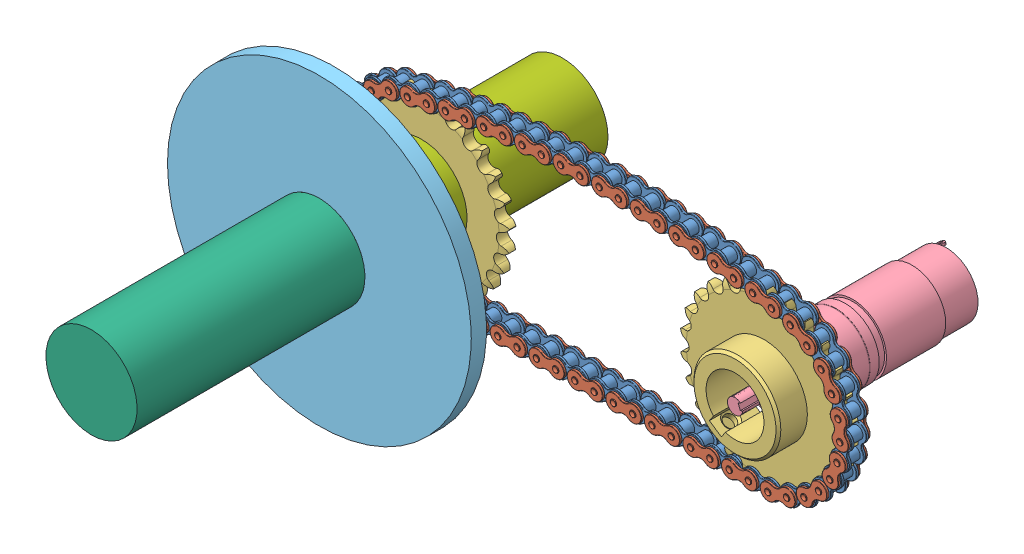
SolidWorks assembly Assem 2, configuration Default. Lengths in mm.
Overall size (403.81 200 344.19).
11 component instances, 7 part files, 6 mates.
Components (placement in the parent):
- chain drive and dc motor-1: chain drive and dc motor [Default] at (729.7386 963.1257 280.6982) x (-1 0 0) z (0 0 1) size (376.19 156.56 146)
  - Chain Drive-1: Chain Drive [Default] at (171.0759 206.2614 266.5858) size (376.19 156.56 30.44)
    - Chain A-1: Chain A [Default] at (-3.9373 5.8722 -1.9118) size (345.06 131.12 15.57)
      - Inner Chain-1: Inner Chain [Default] at (120.3815 217.874 272.3658) size (345.06 131.12 11.1)
      - Outer Chain-1: Outer Chain [Default] at (158.3912 217.874 270.6371) size (343.48 129.27 15.57)
    - Sprocket-1: Sprocket [Default] at (14.8599 170.457 272.397) x (0.831249 -0.555901 0) z (0 0 1) size (113.36 112.54 26.52)
    - Sprocket-2: Sprocket [Default] at (240.2692 170.457 272.397) x (0.94097 0.33849 0) z (0 0 1) size (113.36 112.54 26.52)
  - DC Motor-1: DC Motor [Default] at (185.9358 376.7184 426.2464) x (0.931343 0.364143 0) z (0.364143 -0.931343 0) size (45 146.01 45)
- Disc-1: Disc [Default] at (318.3935 586.4073 884.134) size (200 200 10)
- Shaft 1-1: Shaft 1 [Default] at (319.3555 591.3138 969.134) x (0 0 -1) z (0.981316 -0.192405 0) size (150 60 60)
- Shaft 2-1: Shaft 2 [Default] at (316.4979 591.034 809.134) x (0 0 1) z (-0.92535 -0.379114 0) size (150 60 60)
Mates (geometry in assembly coordinates):
- Coincident1: coincident: circle of assembly; cylinder of assembly; circle of Disc-1; cylinder of Shaft 1-1 through (318.3935 586.4073 1044.134) axis (0 0 -1) radius 30
- Coincident2: coincident: circle of assembly; plane of assembly; plane of Disc-1; plane of Shaft 2-1 through (318.3935 586.4073 884.134) normal (0 0 1)
- Coincident3: coincident: circle of assembly; cylinder of assembly; circle of Disc-1; cylinder of Shaft 1-1 through (318.3935 586.4073 1044.134) axis (0 0 -1) radius 30
- Coincident4: coincident: circle of assembly; circle of assembly; circle of Disc-1; circle of Shaft 1-1
- Coincident5: coincident: circle of assembly; circle of assembly; circle of Disc-1; circle of Shaft 2-1
- Concentric1: concentric: circle of assembly; circle of assembly; circle of chain drive and dc motor-1/Chain Drive-1/Sprocket-2; circle of Shaft 2-1
